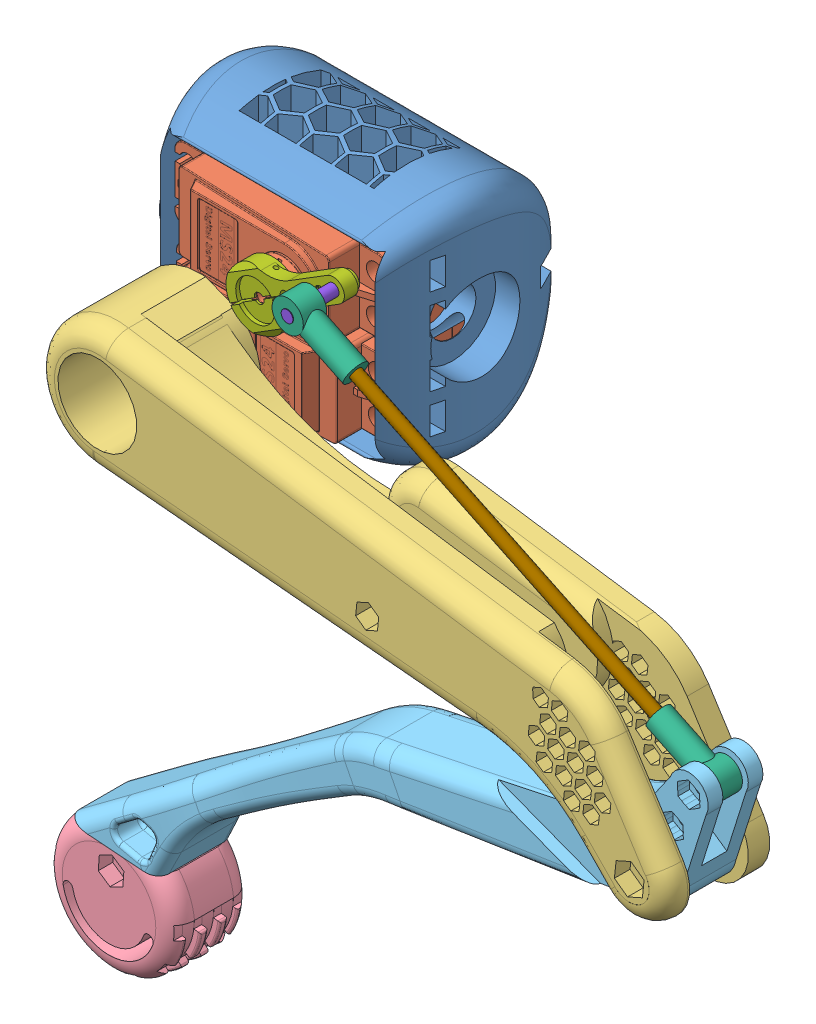
SolidWorks assembly Assem4, configuration Default. Lengths in mm.
Overall size (177.61 172.17 82.41).
11 component instances, 9 part files, 22 mates.
Components (placement in the parent):
- HipJoint-1: HipJoint [Default] at (22.0204 30.6075 56.2648) size (67.23 58.77 49.18)
- DS3218MG_MS24_Digital_Servo_270-1: DS3218MG_MS24_Digital_Servo_270 [Default] at (12.2704 19.5075 70.2648) x (0 1 0) z (1 0 0) size (20.1 45.99 55.6)
- DS3218MG_MS24_Digital_Servo_270-2: DS3218MG_MS24_Digital_Servo_270 [Default] at (31.7704 41.6075 70.2648) x (0 -1 0) z (-1 0 0) size (20.1 45.99 55.6)
- Left_Thigh-1: Left_Thigh [Default] at (71.9435 13.2524 98.0648) x (0 0 1) z (-0.994551 0.104252 0) size (26.29 49.21 165.28)
- Feet-1: Feet [Default] at (13.0242 -85.1033 98.3148) x (0 0 1) z (-0.997222 0.07448 0) size (22.41 28.94 33.85)
- Leg_Universal-1: Leg_Universal [Default] at (76.3635 -45.3476 98.5648) x (0 0 1) z (-0.999481 -0.032213 0) size (27.56 93.87 164.52)
- Ball_Bearing_End_Joint-1: Ball_Bearing_End_Joint [Default] at (158.1198 2.9758 98.8148) x (-0.432528 -0.901621 0) z (0 0 1) size (8 20 6)
- Ball_Bearing_End_Joint-2: Ball_Bearing_End_Joint [Default] at (51.7286 54.0141 98.8148) x (0.432528 0.901621 0) z (0 0 1) size (8 20 6)
- Servo_arm_25T-1: Servo_arm_25T [Default] at (31.7704 41.6075 90.1648) x (-0.849282 -0.52794 0) z (0.52794 -0.849282 0) size (33.87 4.68 15)
- Short_Metal_Rod-1: Short_Metal_Rod [Default] at (51.7286 54.0141 95.5777) size (3 3 16.55)
- Long_Metal_Rod-1: Long_Metal_Rod [Default] at (104.9242 28.4949 98.8148) x (-0.378055 -0.78807 0.48582) z (0.901621 -0.432528 0) size (3 3 100)
Mates (geometry in assembly coordinates):
- Coincident1: coincident anti-aligned: plane of HipJoint-1 through (42.2704 30.6075 42.2648) normal (-1 0 0); plane of DS3218MG MS24 Digital Servo 270-1 through (42.2704 9.5075 50.2648) normal (1 0 0)
- Coincident2: coincident anti-aligned: plane of HipJoint-1 through (22.0204 9.5075 42.2648) normal (0 1 0); plane of DS3218MG MS24 Digital Servo 270-1 through (2.2704 9.5075 50.2648) normal (0 -1 0)
- Coincident3: coincident anti-aligned: plane of HipJoint-1 through (22.0204 30.6075 70.2648) normal (0 0 1); plane of DS3218MG MS24 Digital Servo 270-1 through (39.2704 28.5075 70.2648) normal (0 0 -1)
- Coincident4: coincident anti-aligned: plane of HipJoint-1 through (1.7704 30.6075 42.2648) normal (1 0 0); plane of DS3218MG MS24 Digital Servo 270-2 through (1.7704 51.6075 50.2648) normal (-1 0 0)
- Coincident5: coincident anti-aligned: plane of HipJoint-1 through (22.0204 31.6075 42.2648) normal (0 1 0); plane of DS3218MG MS24 Digital Servo 270-2 through (41.7704 31.6075 50.2648) normal (0 -1 0)
- Coincident6: coincident anti-aligned: plane of HipJoint-1 through (22.0204 30.6075 70.2648) normal (0 0 1); plane of DS3218MG MS24 Digital Servo 270-2 through (4.7704 32.6075 70.2648) normal (0 0 -1)
- Concentric1: concentric aligned: circle of DS3218MG MS24 Digital Servo 270-1; circle of Left Thigh-1
- Distance1: distance = 0 mm anti-aligned: plane of Left Thigh-1 through (12.2704 19.5075 88.6648) normal (0 0 -1); plane of DS3218MG MS24 Digital Servo 270-1 through (12.2704 19.5075 88.6648) normal (0 0 1)
- Concentric2: concentric anti-aligned: circle of Left Thigh-1; circle of Leg_Universal-1
- Distance2: distance = 0 mm anti-aligned: plane of Leg_Universal-1 through (76.3635 -45.3476 105.5648) normal (0 0 1); plane of Left Thigh-1 through (71.9435 13.2524 105.5648) normal (0 0 -1)
- Distance4: distance = 0 mm anti-aligned: plane of Feet-1 through (12.5751 -91.116 102.5648) normal (0 0 -1); plane of Leg_Universal-1 through (76.3635 -45.3476 102.5648) normal (0 0 1)
- Distance3: distance = 0 mm anti-aligned: plane of Leg_Universal-1 through (10.0957 -40.3983 94.5648) normal (-0.997222 0.07448 0); plane of Feet-1 through (6.3425 -90.6505 98.3148) normal (0.997222 -0.07448 0)
- Distance5: distance = 0 mm anti-aligned: plane of Leg_Universal-1 through (73.4295 -84.6305 88.5648) normal (-0.07448 -0.997222 0); plane of Feet-1 through (13.3944 -80.1466 86.509) normal (0.07448 0.997222 0)
- Concentric3: concentric anti-aligned: circle of DS3218MG MS24 Digital Servo 270-2; circle of Servo_arm_25T-1
- Distance7: distance = 0 mm anti-aligned: plane of DS3218MG MS24 Digital Servo 270-2 through (31.7704 41.6075 88.6648) normal (0 0 1); plane of Servo_arm_25T-1 through (31.7704 41.6075 88.6648) normal (0 0 -1)
- Coincident8: coincident aligned: circle of Leg_Universal-1; circle of ball bearing end joint-1
- Concentric4: concentric aligned: circle of Servo_arm_25T-1; circle of short-1
- Concentric5: concentric aligned: cylinder of Ball_Bearing_End_Joint-2 through (51.7286 54.0141 95.8148) axis (0 0 1) radius 1.5; cylinder of Short_Metal_Rod-1 through (51.7286 54.0141 85.4277) axis (0 0 1) radius 1.5
- Concentric6: concentric anti-aligned: circle of ball bearing end joint-1; circle of long-1
- Distance10: distance = 0 mm anti-aligned: plane of ball bearing end joint-1 through (150.0052 6.8685 98.8148) normal (-0.901621 0.432528 0); plane of long-1 through (150.0052 6.8685 98.8148) normal (0.901621 -0.432528 0)
- Concentric8: concentric anti-aligned: cylinder of Ball_Bearing_End_Joint-2 through (48.1221 55.7442 98.8148) axis (-0.901621 0.432528 0) radius 3; cylinder of Long_Metal_Rod-1 through (59.8432 50.1213 98.8148) axis (0.901621 -0.432528 0) radius 1.5
- Coincident17: coincident anti-aligned: plane of Ball_Bearing_End_Joint-2 through (59.8432 50.1213 98.8148) normal (0.901621 -0.432528 0); plane of Long_Metal_Rod-1 through (59.8432 50.1213 98.8148) normal (-0.901621 0.432528 0)
